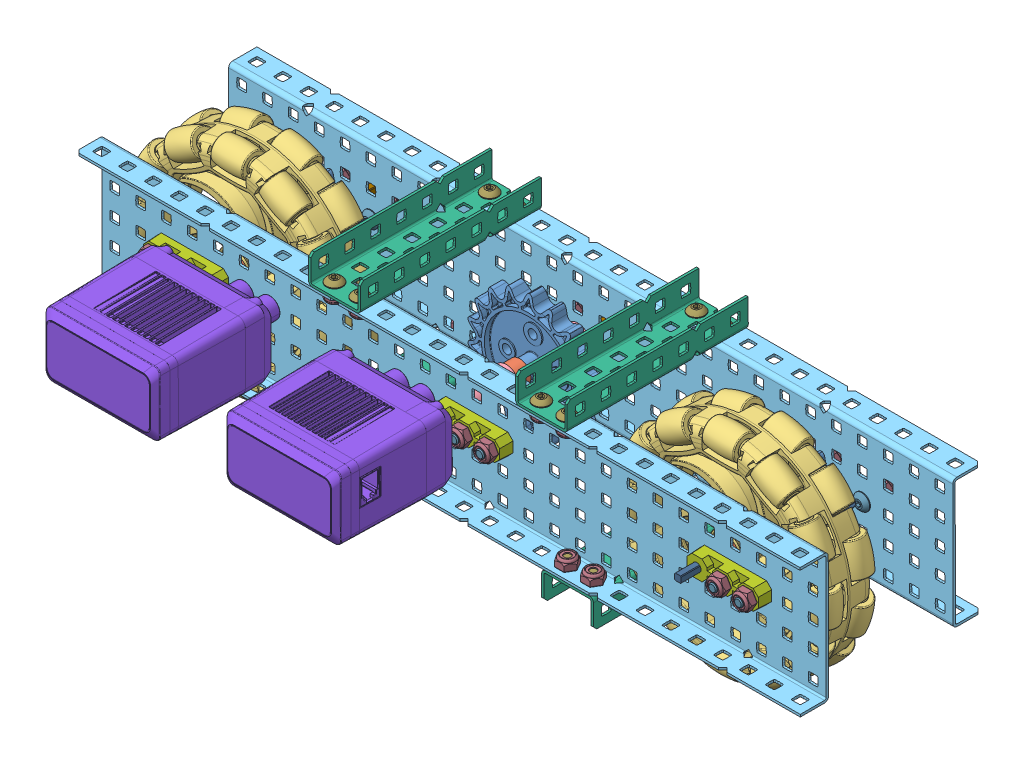
SolidWorks assembly tank_drive_left, configuration Default. Lengths in mm.
Overall size (355.74 109.64 150.55).
92 component instances, 14 part files, 192 mates.
Components (placement in the parent):
- Sprocket HS 18 Tooth-16: Sprocket HS 18 Tooth [Default] at (197.3923 25.5818 -147.38) size (60.62 61.51 15.88)
- Shaft Collar-3: Shaft Collar [Default] at (197.3923 25.5818 -136.1405) size (11 11.03 6.6)
- 4in Omni Directional Wheel-7: 4in Omni Directional Wheel [Default] at (197.3923 25.5818 -123.6356) x (1 0 0) z (0 -1 0) size (111.98 41.89 109.1)
- Sprocket HS 18 Tooth-18: Sprocket HS 18 Tooth [Default] at (311.692 25.8354 -147.38) size (60.62 61.51 15.88)
- Shaft Collar-6: Shaft Collar [Default] at (311.692 25.8354 -136.1405) size (11 11.03 6.6)
- Nylon Spacer .5 .5in-8: Nylon Spacer .5 .5in [Default] at (311.692 25.8354 -126.4885) x (1 0 0) z (0 -1 0) size (12.7 12.7 12.7)
- Sprocket HS 18 Tooth-19: Sprocket HS 18 Tooth [Default] at (438.6917 26.1172 -147.38) size (60.62 61.51 15.88)
- Shaft Collar-7: Shaft Collar [Default] at (438.6917 26.1172 -111.1307) size (11 11.03 6.6)
- Shaft Collar-8: Shaft Collar [Default] at (438.6917 26.1172 -136.1405) size (11 11.03 6.6)
- 4in Omni Directional Wheel-8: 4in Omni Directional Wheel [Default] at (438.6917 26.1172 -123.6356) x (1 0 0) z (0 -1 0) size (111.98 41.89 109.1)
- Shaft Collar-10: Shaft Collar [Default] at (197.3923 25.5818 -111.1307) size (11 11.03 6.6)
- Nylon Spacer .5 .5in-9: Nylon Spacer .5 .5in [Default] at (311.692 25.8354 -113.7885) x (1 0 0) z (0 -1 0) size (12.7 12.7 12.7)
- Nylon Spacer .5 .5in-10: Nylon Spacer .5 .5in [Default] at (438.6917 26.1172 -161.6675) x (1 0 0) z (0 -1 0) size (12.7 12.7 12.7)
- Nylon Spacer .5 .5in-11: Nylon Spacer .5 .5in [Default] at (311.692 25.8354 -161.6675) x (1 0 0) z (0 -1 0) size (12.7 12.7 12.7)
- Nylon Spacer .5 .5in-12: Nylon Spacer .5 .5in [Default] at (197.3923 25.5818 -161.6675) x (1 0 0) z (0 -1 0) size (12.7 12.7 12.7)
- C-Channel 1x5x1x28-6: C-Channel 1x5x1x28 [Default] at (77.7725 41.2118 -169.1859) x (0.999998 0.002219 0) z (0.002219 -0.999998 0) size (355.6 13.87 63.5)
- C-Channel 1x2x1x7-3: C-Channel 1x2x1x7 [Default] at (384.516 -7.1755 -119.4512) x (0 0 -1) z (0.999998 0.002219 0) size (88.9 13.87 25.4)
- C-Channel 1x5x1x28-7: C-Channel 1x5x1x28 [Default] at (558.2409 42.278 -105.6859) x (-0.999998 -0.002219 0) z (0.002219 -0.999998 0) size (355.6 13.87 63.5)
- Bearing Flat-7: Bearing Flat [Default] at (211.0801 38.3122 -16.7097) x (0 0 -1) z (-0.002219 0.999998 0) size (7.04 35.56 10.16)
- Bearing Flat-8: Bearing Flat [Default] at (350.7797 38.6222 -16.7097) x (0 0 -1) z (-0.002219 0.999998 0) size (7.04 35.56 10.16)
- Bearing Flat-9: Bearing Flat [Default] at (425.0039 13.3868 -16.7097) x (0 0 -1) z (0.002219 -0.999998 0) size (7.04 35.56 10.16)
- Bearing Flat-10: Bearing Flat [Default] at (465.1358 13.4759 -258.1621) x (0 0 1) z (0.00222 -0.999998 0) size (7.04 35.56 10.16)
- Bearing Flat-11: Bearing Flat [Default] at (338.1361 13.1941 -258.1621) x (0 0 1) z (0.002219 -0.999998 0) size (7.04 35.56 10.16)
- Bearing Flat-12: Bearing Flat [Default] at (223.8364 12.9404 -258.1621) x (0 0 1) z (0.00222 -0.999998 0) size (7.04 35.56 10.16)
- V5 Smart Motor-1: V5 Smart Motor [Default] at (210.0922 25.6099 -61.4859) x (-0.999998 -0.002219 0) z (0 0 -1) size (57.3 33 72.31)
- V5 Smart Motor-2: V5 Smart Motor [Default] at (298.992 25.8072 -61.4859) x (0.999998 0.002219 0) z (0 0 -1) size (57.3 33 72.31)
- Drive Shaft 4-inches long-1: Drive Shaft 4-inches long [Default] at (197.3923 25.5818 120.1773) x (-1 0 0) z (0 0 -1) size (3.17 3.17 101.34)
- Drive Shaft 4-inches long-2: Drive Shaft 4-inches long [Default] at (311.692 25.8354 120.1773) x (-1 0 0) z (0 0 -1) size (3.17 3.17 101.34)
- Drive Shaft 3.5-inches long-1: Drive Shaft 3.5-inches long [Default] at (438.6917 26.1172 126.0171) x (-1 0 0) z (0 0 -1) size (3.17 3.17 88.64)
- C-Channel 1x2x1x7-4: C-Channel 1x2x1x7 [Default] at (257.5163 -7.4573 -119.4512) x (0 0 -1) z (0.999998 0.002219 0) size (88.9 13.87 25.4)
- C-Channel 1x2x1x7-5: C-Channel 1x2x1x7 [Default] at (264.2691 58.3946 -119.4512) x (0 0 -1) z (-0.999998 -0.002219 0) size (88.9 13.87 25.4)
- C-Channel 1x2x1x7-6: C-Channel 1x2x1x7 [Default] at (365.8688 58.6201 -119.4512) x (0 0 -1) z (-0.999998 -0.002219 0) size (88.9 13.87 25.4)
- Screw 632 .25in-1: Screw 632 .25in [Default] at (222.7922 25.6381 -108.7085) x (0 0 1) z (-1 0 0) size (8.57 6.68 6.65)
- Screw 632 .25in-2: Screw 632 .25in [Default] at (210.0922 25.6099 -108.7085) x (0 0 1) z (-1 0 0) size (8.57 6.68 6.65)
- Screw 632 .25in-3: Screw 632 .25in [Default] at (286.2921 25.779 -108.7085) x (0 0 1) z (-1 0 0) size (8.57 6.68 6.65)
- Screw 632 .25in-4: Screw 632 .25in [Default] at (298.992 25.8072 -108.7085) x (0 0 1) z (-1 0 0) size (8.57 6.68 6.65)
- Screw 832 .25in-1: Screw 832 .25in [Default] at (362.4145 60.8223 -175.5359) x (0.002219 -0.999998 0) z (0 0 1) size (9.01 8.02 7.99)
- Screw 832 .25in-2: Screw 832 .25in [Default] at (387.9703 -9.3776 -175.5359) x (-0.002219 0.999998 0) z (-0.546742 -0.001213 0.8373) size (9.01 8.02 7.99)
- Screw 832 .25in-3: Screw 832 .25in [Default] at (248.2707 -9.6876 -175.5359) x (-0.002219 0.999998 0) z (0 0 1) size (9.01 8.02 7.99)
- Screw 832 .25in-4: Screw 832 .25in [Default] at (260.9706 -9.6594 -175.5359) x (-0.002219 0.999998 0) z (-0.546742 -0.001213 0.8373) size (9.01 8.02 7.99)
- Screw 832 .25in-5: Screw 832 .25in [Default] at (260.8147 60.5968 -175.5359) x (0.002219 -0.999998 0) z (0 0 1) size (9.01 8.02 7.99)
- Screw 832 .25in-6: Screw 832 .25in [Default] at (273.5147 60.625 -175.5359) x (0.002219 -0.999998 0) z (0 0 1) size (9.01 8.02 7.99)
- Screw 832 .25in-7: Screw 832 .25in [Default] at (375.2704 -9.4058 -175.5359) x (-0.002219 0.999998 0) z (-0.546742 -0.001213 0.8373) size (9.01 8.02 7.99)
- Screw 832 .25in-8: Screw 832 .25in [Default] at (375.1144 60.8504 -175.5359) x (0.002219 -0.999998 0) z (0 0 1) size (9.01 8.02 7.99)
- Screw 832 .25in-9: Screw 832 .25in [Default] at (248.2707 -9.6876 -99.3359) x (-0.002219 0.999998 0) z (-0.546742 -0.001213 0.8373) size (9.01 8.02 7.99)
- Screw 832 .25in-10: Screw 832 .25in [Default] at (273.5147 60.625 -99.3359) x (0.002219 -0.999998 0) z (0 0 1) size (9.01 8.02 7.99)
- Screw 832 .25in-11: Screw 832 .25in [Default] at (260.9706 -9.6594 -99.3359) x (-0.002219 0.999998 0) z (-0.546742 -0.001213 0.8373) size (9.01 8.02 7.99)
- Screw 832 .25in-12: Screw 832 .25in [Default] at (260.8147 60.5968 -99.3359) x (0.002219 -0.999998 0) z (0 0 1) size (9.01 8.02 7.99)
- Screw 832 .25in-13: Screw 832 .25in [Default] at (375.2704 -9.4058 -99.3359) x (-0.002219 0.999998 0) z (-0.546742 -0.001213 0.8373) size (9.01 8.02 7.99)
- Screw 832 .25in-14: Screw 832 .25in [Default] at (362.4145 60.8223 -99.3359) x (0.002219 -0.999998 0) z (0 0 1) size (9.01 8.02 7.99)
- Screw 832 .25in-15: Screw 832 .25in [Default] at (387.9703 -9.3776 -99.3359) x (-0.002219 0.999998 0) z (-0.546742 -0.001213 0.8373) size (9.01 8.02 7.99)
- Screw 832 .25in-16: Screw 832 .25in [Default] at (375.1144 60.8504 -99.3359) x (0.002219 -0.999998 0) z (0 0 1) size (9.01 8.02 7.99)
- Nut 832 Nylock-1: Nut 832 Nylock [Default] at (387.9602 -4.831 -175.5359) x (0.999998 0.002219 0) z (0 0 1) size (10.2 4.9 8.12)
- Nut 832 Nylock-2: Nut 832 Nylock [Default] at (375.2603 -4.8592 -175.5359) x (0.999998 0.002219 0) z (0 0 1) size (10.2 4.9 8.12)
- Nut 832 Nylock-3: Nut 832 Nylock [Default] at (260.9605 -5.1129 -175.5359) x (0.999998 0.002219 0) z (0 0 1) size (10.2 4.9 8.12)
- Nut 832 Nylock-4: Nut 832 Nylock [Default] at (248.2606 -5.141 -175.5359) x (0.999998 0.002219 0) z (0 0 1) size (10.2 4.9 8.12)
- Nut 832 Nylock-5: Nut 832 Nylock [Default] at (260.8248 56.0502 -175.5359) x (-0.837298 -0.001858 -0.546743) z (-0.546742 -0.001213 0.8373) size (10.2 4.9 8.12)
- Nut 832 Nylock-6: Nut 832 Nylock [Default] at (273.5248 56.0784 -175.5359) x (-0.837298 -0.001858 -0.546743) z (-0.546742 -0.001213 0.8373) size (10.2 4.9 8.12)
- Nut 832 Nylock-7: Nut 832 Nylock [Default] at (362.4246 56.2757 -175.5359) x (-0.837298 -0.001858 -0.546743) z (-0.546742 -0.001213 0.8373) size (10.2 4.9 8.12)
- Nut 832 Nylock-8: Nut 832 Nylock [Default] at (375.1245 56.3038 -175.5359) x (-0.837298 -0.001858 -0.546743) z (-0.546742 -0.001213 0.8373) size (10.2 4.9 8.12)
- Nut 832 Nylock-9: Nut 832 Nylock [Default] at (387.9602 -4.831 -99.3359) x (0.999998 0.002219 0) z (0 0 1) size (10.2 4.9 8.12)
- Nut 832 Nylock-10: Nut 832 Nylock [Default] at (375.2603 -4.8592 -99.3359) x (0.999998 0.002219 0) z (0 0 1) size (10.2 4.9 8.12)
- Nut 832 Nylock-11: Nut 832 Nylock [Default] at (260.9605 -5.1129 -99.3359) x (0.999998 0.002219 0) z (0 0 1) size (10.2 4.9 8.12)
- Nut 832 Nylock-12: Nut 832 Nylock [Default] at (248.2606 -5.141 -99.3359) x (0.999998 0.002219 0) z (0 0 1) size (10.2 4.9 8.12)
- Nut 832 Nylock-13: Nut 832 Nylock [Default] at (260.8248 56.0502 -99.3359) x (-0.837298 -0.001858 -0.546743) z (-0.546742 -0.001213 0.8373) size (10.2 4.9 8.12)
- Nut 832 Nylock-14: Nut 832 Nylock [Default] at (273.5248 56.0784 -99.3359) x (-0.837298 -0.001858 -0.546743) z (-0.546742 -0.001213 0.8373) size (10.2 4.9 8.12)
- Nut 832 Nylock-15: Nut 832 Nylock [Default] at (362.4246 56.2757 -99.3359) x (-0.837298 -0.001858 -0.546743) z (-0.546742 -0.001213 0.8373) size (10.2 4.9 8.12)
- Nut 832 Nylock-16: Nut 832 Nylock [Default] at (375.1245 56.3038 -99.3359) x (-0.837298 -0.001858 -0.546743) z (-0.546742 -0.001213 0.8373) size (10.2 4.9 8.12)
- Screw 832 .5in-1: Screw 832 .5in [Default] at (171.9923 25.5254 -109.0641) x (0 0 1) z (-1 0 0) size (15.36 8.02 7.99)
- Screw 832 .5in-2: Screw 832 .5in [Default] at (184.6923 25.5536 -109.0641) x (0 0 1) z (-1 0 0) size (15.36 8.02 7.99)
- Screw 832 .5in-3: Screw 832 .5in [Default] at (324.392 25.8636 -109.0641) x (0 0 1) z (-1 0 0) size (15.36 8.02 7.99)
- Screw 832 .5in-4: Screw 832 .5in [Default] at (337.0919 25.8918 -109.0641) x (0 0 1) z (-1 0 0) size (15.36 8.02 7.99)
- Screw 832 .5in-5: Screw 832 .5in [Default] at (451.3916 26.1454 -109.0641) x (0 0 1) z (-1 0 0) size (15.36 8.02 7.99)
- Screw 832 .5in-6: Screw 832 .5in [Default] at (464.0916 26.1736 -109.0641) x (0 0 1) z (-1 0 0) size (15.36 8.02 7.99)
- Screw 832 .5in-7: Screw 832 .5in [Default] at (451.3916 26.1454 -165.8077) x (0 0 -1) z (1 0 0) size (15.36 8.02 7.99)
- Screw 832 .5in-8: Screw 832 .5in [Default] at (425.9917 26.0891 -165.8077) x (0 0 -1) z (1 0 0) size (15.36 8.02 7.99)
- Screw 832 .5in-9: Screw 832 .5in [Default] at (324.392 25.8636 -165.8077) x (0 0 -1) z (1 0 0) size (15.36 8.02 7.99)
- Screw 832 .5in-10: Screw 832 .5in [Default] at (298.992 25.8072 -165.8077) x (0 0 -1) z (1 0 0) size (15.36 8.02 7.99)
- Screw 832 .5in-11: Screw 832 .5in [Default] at (210.0922 25.61 -165.8077) x (0 0 -1) z (1 0 0) size (15.36 8.02 7.99)
- Screw 832 .5in-12: Screw 832 .5in [Default] at (184.6923 25.5536 -165.8077) x (0 0 -1) z (1 0 0) size (15.36 8.02 7.99)
- Nut 832 Nylock-17: Nut 832 Nylock [Default] at (184.6923 25.5536 -99.3359) x (1 0 0) z (0 -1 0) size (10.2 4.9 8.12)
- Nut 832 Nylock-18: Nut 832 Nylock [Default] at (171.9923 25.5254 -99.3359) x (1 0 0) z (0 -1 0) size (10.2 4.9 8.12)
- Nut 832 Nylock-19: Nut 832 Nylock [Default] at (324.392 25.8636 -99.3359) x (1 0 0) z (0 -1 0) size (10.2 4.9 8.12)
- Nut 832 Nylock-20: Nut 832 Nylock [Default] at (337.0919 25.8918 -99.3359) x (1 0 0) z (0 -1 0) size (10.2 4.9 8.12)
- Nut 832 Nylock-21: Nut 832 Nylock [Default] at (451.3916 26.1454 -99.3359) x (1 0 0) z (0 -1 0) size (10.2 4.9 8.12)
- Nut 832 Nylock-22: Nut 832 Nylock [Default] at (464.0916 26.1736 -99.3359) x (1 0 0) z (0 -1 0) size (10.2 4.9 8.12)
- Nut 832 Nylock-23: Nut 832 Nylock [Default] at (451.3916 26.1454 -175.5359) x (1 0 0) z (0 1 0) size (10.2 4.9 8.12)
- Nut 832 Nylock-24: Nut 832 Nylock [Default] at (425.9917 26.0891 -175.5359) x (1 0 0) z (0 1 0) size (10.2 4.9 8.12)
- Nut 832 Nylock-25: Nut 832 Nylock [Default] at (324.392 25.8636 -175.5359) x (1 0 0) z (0 1 0) size (10.2 4.9 8.12)
- Nut 832 Nylock-26: Nut 832 Nylock [Default] at (298.992 25.8072 -175.5359) x (1 0 0) z (0 1 0) size (10.2 4.9 8.12)
- Nut 832 Nylock-27: Nut 832 Nylock [Default] at (210.0922 25.61 -175.5359) x (1 0 0) z (0 1 0) size (10.2 4.9 8.12)
- Nut 832 Nylock-28: Nut 832 Nylock [Default] at (184.6923 25.5536 -175.5359) x (1 0 0) z (0 1 0) size (10.2 4.9 8.12)
Mates (geometry in assembly coordinates):
- Concentric110: concentric: cylinder of Sprocket HS 18 Tooth-16 through (197.3923 25.5818 -132.4575) axis (0 0 -1) radius 1.651; cylinder of Shaft Collar-3 through (197.3923 25.5818 -139.4425) axis (0 0 1) radius 2.0955
- Coincident75: coincident: plane of Sprocket HS 18 Tooth-16 through (197.3923 25.5818 -139.4425) normal (0 0 1); circle of Shaft Collar-3
- Concentric111: concentric: cylinder of Shaft Collar-3 through (197.3923 25.5818 -139.4425) axis (0 0 1) radius 2.0955; cylinder of 4in Omni Directional Wheel-7 through (197.3923 25.5818 -155.0046) axis (0 0 1) radius 1.651
- Tangent19: tangent: plane of Shaft Collar-3 through (197.3923 25.5818 -132.8385) normal (0 0 1); sphere of 4in Omni Directional Wheel-7
- Concentric115: concentric: cylinder of Sprocket HS 18 Tooth-18 through (311.692 25.8354 -132.4575) axis (0 0 -1) radius 1.651; cylinder of Shaft Collar-6 through (311.692 25.8354 -139.4425) axis (0 0 1) radius 2.0955
- Coincident78: coincident: plane of Sprocket HS 18 Tooth-18 through (311.692 25.8354 -139.4425) normal (0 0 1); plane of Shaft Collar-6 through (311.692 25.8354 -139.4425) normal (0 0 -1)
- Concentric116: concentric: cylinder of Shaft Collar-6 through (311.692 25.8354 -139.4425) axis (0 0 1) radius 2.0955; cylinder of Nylon Spacer .5 .5in-8 through (311.692 25.8354 -120.1385) axis (0 0 -1) radius 2.4638
- Coincident79: coincident: plane of Shaft Collar-6 through (311.692 25.8354 -132.8385) normal (0 0 1); circle of Nylon Spacer .5 .5in-8
- Concentric141: concentric: cylinder of Sprocket HS 18 Tooth-19 through (438.6917 26.1172 -132.4575) axis (0 0 -1) radius 1.651; cylinder of Shaft Collar-8 through (438.6917 26.1172 -139.4425) axis (0 0 1) radius 2.0955
- Coincident91: coincident: plane of Sprocket HS 18 Tooth-19 through (438.6917 26.1172 -139.4425) normal (0 0 1); plane of Shaft Collar-8 through (438.6917 26.1172 -139.4425) normal (0 0 -1)
- Concentric142: concentric: cylinder of Shaft Collar-8 through (438.6917 26.1172 -139.4425) axis (0 0 1) radius 2.0955; cylinder of 4in Omni Directional Wheel-8 through (438.6917 26.1172 -155.0046) axis (0 0 1) radius 1.651
- Tangent20: tangent: plane of Shaft Collar-8 through (438.6917 26.1172 -132.8385) normal (0 0 1); sphere of 4in Omni Directional Wheel-8
- Concentric143: concentric: cylinder of Shaft Collar-7 through (438.6917 26.1172 -114.4327) axis (0 0 1) radius 2.0955; cylinder of 4in Omni Directional Wheel-8 through (438.6917 26.1172 -155.0046) axis (0 0 1) radius 1.651
- Tangent21: tangent: plane of Shaft Collar-7 through (438.6917 26.1172 -114.4327) normal (0 0 -1); sphere of 4in Omni Directional Wheel-8
- Concentric146: concentric: cylinder of 4in Omni Directional Wheel-7 through (197.3923 25.5818 -155.0046) axis (0 0 1) radius 1.651; cylinder of Shaft Collar-10 through (197.3923 25.5818 -114.4327) axis (0 0 1) radius 2.0955
- Tangent22: tangent: sphere of 4in Omni Directional Wheel-7; plane of Shaft Collar-10 through (197.3923 25.5818 -114.4327) normal (0 0 -1)
- Coincident96: coincident: circle of Nylon Spacer .5 .5in-8; cylinder of Nylon Spacer .5 .5in-9 through (311.692 25.8354 -107.4385) axis (0 0 -1) radius 2.4638
- Coincident97: coincident: circle of Nylon Spacer .5 .5in-8; circle of Nylon Spacer .5 .5in-9
- Concentric151: concentric: cylinder of Sprocket HS 18 Tooth-19 through (438.6917 26.1172 -132.4575) axis (0 0 -1) radius 1.651; circle of Nylon Spacer .5 .5in-10
- Coincident98: coincident: plane of Sprocket HS 18 Tooth-19 through (438.6917 26.1172 -155.3175) normal (0 0 -1); plane of Nylon Spacer .5 .5in-10 through (438.6917 26.1172 -155.3175) normal (0 0 1)
- Concentric152: concentric: cylinder of Sprocket HS 18 Tooth-18 through (311.692 25.8354 -132.4575) axis (0 0 -1) radius 1.651; cylinder of Nylon Spacer .5 .5in-11 through (311.692 25.8354 -155.3175) axis (0 0 -1) radius 2.4638
- Coincident99: coincident: plane of Sprocket HS 18 Tooth-18 through (311.692 25.8354 -155.3175) normal (0 0 -1); circle of Nylon Spacer .5 .5in-11
- Concentric153: concentric: cylinder of Sprocket HS 18 Tooth-16 through (197.3923 25.5818 -132.4575) axis (0 0 -1) radius 1.651; cylinder of Nylon Spacer .5 .5in-12 through (197.3923 25.5818 -155.3175) axis (0 0 -1) radius 2.4638
- Coincident100: coincident: plane of Sprocket HS 18 Tooth-16 through (197.3923 25.5818 -155.3175) normal (0 0 -1); circle of Nylon Spacer .5 .5in-12
- Concentric154: concentric: cylinder of Nylon Spacer .5 .5in-10 through (438.6917 26.1172 -155.3175) axis (0 0 -1) radius 2.4638; cylinder of C-Channel 1x5x1x28-6 through (438.6917 26.1172 -170.5575) axis (0 0 1) radius 2.413
- Concentric155: concentric: cylinder of Nylon Spacer .5 .5in-12 through (197.3923 25.5818 -155.3175) axis (0 0 -1) radius 2.4638; cylinder of C-Channel 1x5x1x28-6 through (197.3923 25.5818 -170.5575) axis (0 0 1) radius 2.413
- Coincident101: coincident: plane of Nylon Spacer .5 .5in-12 through (197.3923 25.5818 -168.0175) normal (0 0 -1); plane of C-Channel 1x5x1x28-6 through (51.4137 -6.7463 -168.0175) normal (0 0 1)
- Concentric156: concentric: cylinder of Nylon Spacer .5 .5in-11 through (311.692 25.8354 -155.3175) axis (0 0 -1) radius 2.4638; cylinder of C-Channel 1x5x1x28-6 through (311.692 25.8354 -170.5575) axis (0 0 1) radius 2.413
- Concentric157: concentric: cylinder of C-Channel 1x5x1x28-6 through (387.8219 57.5004 -175.5359) axis (0.002219 -0.999998 0) radius 2.413; cylinder of C-Channel 1x2x1x7-3 through (387.9685 -8.5394 -175.5359) axis (-0.002219 0.999998 0) radius 2.413
- Concentric158: concentric: cylinder of C-Channel 1x5x1x28-6 through (375.1219 57.4722 -175.5359) axis (0.002219 -0.999998 0) radius 2.413; cylinder of C-Channel 1x2x1x7-3 through (375.2685 -8.5676 -175.5359) axis (-0.002219 0.999998 0) radius 2.413
- Coincident102: coincident: plane of C-Channel 1x5x1x28-6 through (51.4137 -6.7463 -181.8859) normal (0.002219 -0.999998 0); plane of C-Channel 1x2x1x7-3 through (394.3128 -5.9853 -92.9859) normal (-0.002219 0.999998 0)
- Concentric159: concentric: cylinder of C-Channel 1x2x1x7-3 through (387.9685 -8.5394 -99.3359) axis (-0.002219 0.999998 0) radius 2.413; cylinder of C-Channel 1x5x1x28-7 through (387.8219 57.5004 -99.3359) axis (0.002219 -0.999998 0) radius 2.413
- Concentric160: concentric: cylinder of C-Channel 1x2x1x7-3 through (375.2685 -8.5676 -99.3359) axis (-0.002219 0.999998 0) radius 2.413; cylinder of C-Channel 1x5x1x28-7 through (375.1219 57.4722 -99.3359) axis (0.002219 -0.999998 0) radius 2.413
- Coincident103: coincident: plane of C-Channel 1x2x1x7-3 through (394.3128 -5.9853 -92.9859) normal (-0.002219 0.999998 0); plane of C-Channel 1x5x1x28-7 through (584.8123 -5.5626 -92.9859) normal (0.002219 -0.999998 0)
- Concentric161: concentric: cylinder of C-Channel 1x5x1x28-7 through (197.3923 25.5818 -104.3143) axis (0 0 -1) radius 2.413; cylinder of Bearing Flat-7 through (197.3923 25.5818 -99.3359) axis (0 0 -1) radius 2.1209
- Concentric162: concentric: cylinder of C-Channel 1x5x1x28-7 through (171.9923 25.5254 -104.3143) axis (0 0 -1) radius 2.413; cylinder of Bearing Flat-7 through (171.9923 25.5254 -99.3359) axis (0 0 -1) radius 2.1209
- Coincident104: coincident: plane of C-Channel 1x5x1x28-7 through (584.8123 -5.5626 -105.6859) normal (0 0 1); plane of Bearing Flat-7 through (166.9199 20.4304 -105.6859) normal (0 0 -1)
- Concentric163: concentric: cylinder of C-Channel 1x5x1x28-7 through (337.0919 25.8918 -104.3143) axis (0 0 -1) radius 2.413; cylinder of Bearing Flat-8 through (337.0919 25.8918 -99.3359) axis (0 0 -1) radius 2.1209
- Concentric164: concentric: cylinder of C-Channel 1x5x1x28-7 through (311.692 25.8354 -104.3143) axis (0 0 -1) radius 2.413; cylinder of Bearing Flat-8 through (311.692 25.8354 -99.3359) axis (0 0 -1) radius 2.1209
- Coincident105: coincident: plane of C-Channel 1x5x1x28-7 through (584.8123 -5.5626 -105.6859) normal (0 0 1); plane of Bearing Flat-8 through (306.6196 20.7405 -105.6859) normal (0 0 -1)
- Concentric165: concentric: cylinder of C-Channel 1x5x1x28-7 through (438.6917 26.1172 -104.3143) axis (0 0 -1) radius 2.413; cylinder of Bearing Flat-9 through (438.6917 26.1172 -99.3359) axis (0 0 -1) radius 2.1209
- Concentric166: concentric: cylinder of C-Channel 1x5x1x28-7 through (464.0916 26.1736 -104.3143) axis (0 0 -1) radius 2.413; cylinder of Bearing Flat-9 through (464.0916 26.1736 -99.3359) axis (0 0 -1) radius 2.1209
- Coincident106: coincident: plane of C-Channel 1x5x1x28-7 through (584.8123 -5.5626 -105.6859) normal (0 0 1); plane of Bearing Flat-9 through (469.164 31.2686 -105.6859) normal (0 0 -1)
- Concentric167: concentric: cylinder of C-Channel 1x5x1x28-6 through (438.6917 26.1172 -170.5575) axis (0 0 1) radius 2.413; cylinder of Bearing Flat-10 through (438.6917 26.1172 -169.1859) axis (0 0 -1) radius 2.1209
- Concentric168: concentric: cylinder of C-Channel 1x5x1x28-6 through (425.9917 26.0891 -170.5575) axis (0 0 1) radius 2.413; cylinder of Bearing Flat-10 through (425.9917 26.0891 -175.5359) axis (0 0 1) radius 2.1209
- Coincident107: coincident: plane of C-Channel 1x5x1x28-6 through (51.4137 -6.7463 -169.1859) normal (0 0 -1); plane of Bearing Flat-10 through (420.8968 31.1614 -169.1859) normal (0 0 1)
- Concentric169: concentric: cylinder of C-Channel 1x5x1x28-6 through (311.692 25.8354 -170.5575) axis (0 0 1) radius 2.413; cylinder of Bearing Flat-11 through (311.692 25.8354 -169.1859) axis (0 0 -1) radius 2.1209
- Concentric170: concentric: cylinder of C-Channel 1x5x1x28-6 through (324.392 25.8636 -170.5575) axis (0 0 1) radius 2.413; cylinder of Bearing Flat-11 through (324.392 25.8636 -175.5359) axis (0 0 1) radius 2.1209
- Coincident108: coincident: plane of C-Channel 1x5x1x28-6 through (51.4137 -6.7463 -169.1859) normal (0 0 -1); plane of Bearing Flat-11 through (293.8971 30.8796 -169.1859) normal (0 0 1)
- Concentric171: concentric: cylinder of C-Channel 1x5x1x28-6 through (197.3923 25.5818 -170.5575) axis (0 0 1) radius 2.413; cylinder of Bearing Flat-12 through (197.3923 25.5818 -169.1859) axis (0 0 -1) radius 2.1209
- Concentric172: concentric: cylinder of C-Channel 1x5x1x28-6 through (184.6923 25.5536 -170.5575) axis (0 0 1) radius 2.413; cylinder of Bearing Flat-12 through (184.6923 25.5536 -175.5359) axis (0 0 1) radius 2.1209
- Coincident109: coincident: plane of C-Channel 1x5x1x28-6 through (51.4137 -6.7463 -169.1859) normal (0 0 -1); plane of Bearing Flat-12 through (179.5974 30.626 -169.1859) normal (0 0 1)
- Concentric173: concentric: cylinder of C-Channel 1x5x1x28-7 through (222.7922 25.6381 -104.3143) axis (0 0 -1) radius 2.413; cylinder of V5 Smart Motor-1 through (222.7922 25.6381 -106.3859) axis (0 0 -1) radius 1.7272
- Concentric174: concentric: cylinder of C-Channel 1x5x1x28-7 through (210.0922 25.6099 -104.3143) axis (0 0 -1) radius 2.413; cylinder of V5 Smart Motor-1 through (210.0922 25.6099 -106.3859) axis (0 0 -1) radius 1.7272
- Coincident110: coincident: plane of C-Channel 1x5x1x28-7 through (584.8123 -5.5626 -105.6859) normal (0 0 1); plane of V5 Smart Motor-1 through (210.0922 25.6099 -105.6859) normal (0 0 -1)
- Concentric175: concentric: cylinder of C-Channel 1x5x1x28-7 through (286.2921 25.779 -104.3143) axis (0 0 -1) radius 2.413; cylinder of V5 Smart Motor-2 through (286.2921 25.779 -106.3859) axis (0 0 -1) radius 1.7272
- Concentric176: concentric: cylinder of C-Channel 1x5x1x28-7 through (298.992 25.8072 -104.3143) axis (0 0 -1) radius 2.413; cylinder of V5 Smart Motor-2 through (298.992 25.8072 -106.3859) axis (0 0 -1) radius 1.7272
- Coincident111: coincident: plane of C-Channel 1x5x1x28-7 through (584.8123 -5.5626 -105.6859) normal (0 0 1); plane of V5 Smart Motor-2 through (298.992 25.8072 -105.6859) normal (0 0 -1)
- Concentric177: concentric: cylinder of Bearing Flat-12 through (197.3923 25.5818 -169.1859) axis (0 0 -1) radius 2.1209; sphere of Drive Shaft 4-inches long-1
- Coincident112: coincident: plane of V5 Smart Motor-1 through (197.3923 25.5818 -83.2859) normal (0 0 -1); plane of Drive Shaft 4-inches long-1 through (198.9798 23.9943 -83.2859) normal (0 0 1)
- Concentric178: concentric: cylinder of Bearing Flat-11 through (311.692 25.8354 -169.1859) axis (0 0 -1) radius 2.1209; sphere of Drive Shaft 4-inches long-2
- Coincident113: coincident: plane of V5 Smart Motor-2 through (311.692 25.8354 -83.2859) normal (0 0 -1); plane of Drive Shaft 4-inches long-2 through (313.2795 24.2479 -83.2859) normal (0 0 1)
- Concentric179: concentric: cylinder of Bearing Flat-10 through (438.6917 26.1172 -169.1859) axis (0 0 -1) radius 2.1209; sphere of Drive Shaft 3.5-inches long-1
- Concentric180: concentric: cylinder of C-Channel 1x5x1x28-6 through (260.8222 57.2186 -175.5359) axis (0.002219 -0.999998 0) radius 2.413; cylinder of C-Channel 1x2x1x7-4 through (260.9688 -8.8212 -175.5359) axis (-0.002219 0.999998 0) radius 2.413
- Concentric181: concentric: cylinder of C-Channel 1x5x1x28-6 through (248.1223 57.1904 -175.5359) axis (0.002219 -0.999998 0) radius 2.413; cylinder of C-Channel 1x2x1x7-4 through (248.2688 -8.8494 -175.5359) axis (-0.002219 0.999998 0) radius 2.413
- Coincident114: coincident: line of C-Channel 1x5x1x28-6 through (243.9402 -6.319 -181.8859) axis (0.999998 0.002219 0); plane of C-Channel 1x2x1x7-4 through (267.3131 -6.2672 -92.9859) normal (-0.002219 0.999998 0)
- Concentric182: concentric: cylinder of C-Channel 1x5x1x28-7 through (248.1223 57.1904 -99.3359) axis (0.002219 -0.999998 0) radius 2.413; cylinder of C-Channel 1x2x1x7-4 through (248.2688 -8.8494 -99.3359) axis (-0.002219 0.999998 0) radius 2.413
- Concentric183: concentric: cylinder of C-Channel 1x5x1x28-6 through (362.422 57.4441 -175.5359) axis (0.002219 -0.999998 0) radius 2.413; cylinder of C-Channel 1x2x1x7-6 through (362.4163 59.9841 -175.5359) axis (0.002219 -0.999998 0) radius 2.413
- Concentric184: concentric: cylinder of C-Channel 1x5x1x28-7 through (375.1219 57.4722 -99.3359) axis (0.002219 -0.999998 0) radius 2.413; cylinder of C-Channel 1x2x1x7-6 through (375.1163 60.0122 -99.3359) axis (0.002219 -0.999998 0) radius 2.413
- Coincident115: coincident: plane of C-Channel 1x5x1x28-6 through (51.2727 56.7536 -169.1859) normal (-0.002219 0.999998 0); plane of C-Channel 1x2x1x7-6 through (356.072 57.43 -92.9859) normal (0.002219 -0.999998 0)
- Concentric185: concentric: cylinder of C-Channel 1x5x1x28-6 through (260.8222 57.2186 -175.5359) axis (0.002219 -0.999998 0) radius 2.413; cylinder of C-Channel 1x2x1x7-5 through (260.8166 59.7586 -175.5359) axis (0.002219 -0.999998 0) radius 2.413
- Concentric186: concentric: cylinder of C-Channel 1x5x1x28-7 through (273.5222 57.2468 -99.3359) axis (0.002219 -0.999998 0) radius 2.413; cylinder of C-Channel 1x2x1x7-5 through (273.5166 59.7868 -99.3359) axis (0.002219 -0.999998 0) radius 2.413
- Coincident116: coincident: plane of C-Channel 1x5x1x28-6 through (51.2727 56.7536 -169.1859) normal (-0.002219 0.999998 0); plane of C-Channel 1x2x1x7-5 through (254.4722 57.2045 -92.9859) normal (0.002219 -0.999998 0)
- Concentric187: concentric: cylinder of V5 Smart Motor-1 through (222.7922 25.6381 -106.3859) axis (0 0 -1) radius 1.7272; cylinder of Screw 632 .25in-1 through (222.7922 25.6381 -108.7085) axis (0 0 -1) radius 1.7082
- Concentric188: concentric: cylinder of V5 Smart Motor-1 through (210.0922 25.6099 -106.3859) axis (0 0 -1) radius 1.7272; cylinder of Screw 632 .25in-2 through (210.0922 25.6099 -108.7085) axis (0 0 -1) radius 1.7082
- Coincident117: coincident: plane of C-Channel 1x5x1x28-7 through (584.8123 -5.5626 -106.8543) normal (0 0 -1); plane of Screw 632 .25in-2 through (210.0922 27.3181 -106.8543) normal (0 0 1)
- Coincident118: coincident: plane of C-Channel 1x5x1x28-7 through (584.8123 -5.5626 -106.8543) normal (0 0 -1); plane of Screw 632 .25in-1 through (222.7922 27.3463 -106.8543) normal (0 0 1)
- Concentric189: concentric: cylinder of V5 Smart Motor-2 through (286.2921 25.779 -106.3859) axis (0 0 -1) radius 1.7272; cylinder of Screw 632 .25in-3 through (286.2921 25.779 -108.7085) axis (0 0 -1) radius 1.7082
- Concentric190: concentric: cylinder of V5 Smart Motor-2 through (298.992 25.8072 -106.3859) axis (0 0 -1) radius 1.7272; cylinder of Screw 632 .25in-4 through (298.992 25.8072 -108.7085) axis (0 0 -1) radius 1.7082
- Coincident119: coincident: plane of C-Channel 1x5x1x28-7 through (584.8123 -5.5626 -106.8543) normal (0 0 -1); plane of Screw 632 .25in-3 through (286.2921 27.4872 -106.8543) normal (0 0 1)
- Coincident120: coincident: plane of C-Channel 1x5x1x28-7 through (584.8123 -5.5626 -106.8543) normal (0 0 -1); plane of Screw 632 .25in-4 through (298.992 27.5154 -106.8543) normal (0 0 1)
- Concentric191: concentric: cylinder of C-Channel 1x5x1x28-6 through (260.8222 57.2186 -175.5359) axis (0.002219 -0.999998 0) radius 2.413; cylinder of Screw 832 .25in-4 through (260.9706 -9.6594 -175.5359) axis (0.002219 -0.999998 0) radius 2.0828
- Coincident121: coincident: plane of C-Channel 1x2x1x7-4 through (267.3157 -7.4356 -92.9859) normal (0.002219 -0.999998 0); plane of Screw 832 .25in-4 through (259.2218 -7.4535 -176.6747) normal (-0.002219 0.999998 0)
- Concentric193: concentric: cylinder of C-Channel 1x5x1x28-6 through (248.1223 57.1904 -175.5359) axis (0.002219 -0.999998 0) radius 2.413; cylinder of Screw 832 .25in-3 through (248.2707 -9.6876 -175.5359) axis (0.002219 -0.999998 0) radius 2.0828
- Coincident122: coincident: plane of C-Channel 1x2x1x7-4 through (267.3157 -7.4356 -92.9859) normal (0.002219 -0.999998 0); plane of Screw 832 .25in-3 through (246.183 -7.4825 -175.5359) normal (-0.002219 0.999998 0)
- Concentric194: concentric: cylinder of C-Channel 1x5x1x28-6 through (375.1219 57.4722 -175.5359) axis (0.002219 -0.999998 0) radius 2.413; cylinder of Screw 832 .25in-7 through (375.2704 -9.4058 -175.5359) axis (0.002219 -0.999998 0) radius 2.0828
- Coincident123: coincident: plane of C-Channel 1x2x1x7-3 through (394.3154 -7.1537 -92.9859) normal (0.002219 -0.999998 0); plane of Screw 832 .25in-7 through (373.5215 -7.1999 -176.6747) normal (-0.002219 0.999998 0)
- Concentric195: concentric: cylinder of C-Channel 1x2x1x7-3 through (387.9685 -8.5394 -175.5359) axis (-0.002219 0.999998 0) radius 2.413; cylinder of Screw 832 .25in-2 through (387.9703 -9.3776 -175.5359) axis (0.002219 -0.999998 0) radius 2.0828
- Coincident124: coincident: plane of C-Channel 1x2x1x7-3 through (394.3154 -7.1537 -92.9859) normal (0.002219 -0.999998 0); circle of Screw 832 .25in-2
- Concentric196: concentric: cylinder of C-Channel 1x2x1x7-6 through (375.1163 60.0122 -175.5359) axis (0.002219 -0.999998 0) radius 2.413; cylinder of Screw 832 .25in-8 through (375.1144 60.8504 -175.5359) axis (-0.002219 0.999998 0) radius 2.0828
- Coincident125: coincident: plane of C-Channel 1x2x1x7-6 through (356.0694 58.5984 -92.9859) normal (-0.002219 0.999998 0); plane of Screw 832 .25in-8 through (377.2021 58.6453 -175.5359) normal (0.002219 -0.999998 0)
- Concentric197: concentric: cylinder of C-Channel 1x2x1x7-6 through (362.4163 59.9841 -175.5359) axis (0.002219 -0.999998 0) radius 2.413; cylinder of Screw 832 .25in-1 through (362.4145 60.8223 -175.5359) axis (-0.002219 0.999998 0) radius 2.0828
- Concentric198: concentric: cylinder of C-Channel 1x2x1x7-5 through (273.5166 59.7868 -175.5359) axis (0.002219 -0.999998 0) radius 2.413; cylinder of Screw 832 .25in-6 through (273.5147 60.625 -175.5359) axis (-0.002219 0.999998 0) radius 2.0828
- Coincident129: coincident: line of C-Channel 1x2x1x7-5 through (277.8884 58.4249 -181.8859) axis (-0.999998 -0.002219 0); plane of Screw 832 .25in-6 through (275.6024 58.4198 -175.5359) normal (0.002219 -0.999998 0)
- Concentric199: concentric: cylinder of C-Channel 1x2x1x7-5 through (260.8166 59.7586 -175.5359) axis (0.002219 -0.999998 0) radius 2.413; cylinder of Screw 832 .25in-5 through (260.8147 60.5968 -175.5359) axis (-0.002219 0.999998 0) radius 2.0828
- Coincident130: coincident: plane of C-Channel 1x2x1x7-5 through (254.4696 58.3729 -92.9859) normal (-0.002219 0.999998 0); circle of Screw 832 .25in-5
- Concentric200: concentric: cylinder of C-Channel 1x5x1x28-7 through (248.1223 57.1904 -99.3359) axis (0.002219 -0.999998 0) radius 2.413; cylinder of Screw 832 .25in-9 through (248.2707 -9.6876 -99.3359) axis (0.002219 -0.999998 0) radius 2.0828
- Coincident131: coincident: line of C-Channel 1x2x1x7-4 through (243.897 -7.4875 -92.9859) axis (0.999998 0.002219 0); plane of Screw 832 .25in-9 through (246.5218 -7.4817 -100.4747) normal (-0.002219 0.999998 0)
- Concentric201: concentric: cylinder of C-Channel 1x5x1x28-7 through (260.8222 57.2186 -99.3359) axis (0.002219 -0.999998 0) radius 2.413; cylinder of Screw 832 .25in-11 through (260.9706 -9.6594 -99.3359) axis (0.002219 -0.999998 0) radius 2.0828
- Coincident133: coincident: line of C-Channel 1x2x1x7-4 through (243.897 -7.4875 -92.9859) axis (0.999998 0.002219 0); plane of Screw 832 .25in-11 through (259.2218 -7.4535 -100.4747) normal (-0.002219 0.999998 0)
- Concentric202: concentric: cylinder of C-Channel 1x2x1x7-5 through (260.8166 59.7586 -99.3359) axis (0.002219 -0.999998 0) radius 2.413; cylinder of Screw 832 .25in-12 through (260.8147 60.5968 -99.3359) axis (-0.002219 0.999998 0) radius 2.0828
- Coincident134: coincident: plane of C-Channel 1x2x1x7-5 through (254.4696 58.3729 -92.9859) normal (-0.002219 0.999998 0); circle of Screw 832 .25in-12
- Concentric203: concentric: cylinder of C-Channel 1x2x1x7-5 through (273.5166 59.7868 -99.3359) axis (0.002219 -0.999998 0) radius 2.413; cylinder of Screw 832 .25in-10 through (273.5147 60.625 -99.3359) axis (-0.002219 0.999998 0) radius 2.0828
- Coincident135: coincident: plane of C-Channel 1x2x1x7-5 through (254.4696 58.3729 -92.9859) normal (-0.002219 0.999998 0); circle of Screw 832 .25in-10
- Concentric204: concentric: cylinder of C-Channel 1x5x1x28-7 through (375.1219 57.4722 -99.3359) axis (0.002219 -0.999998 0) radius 2.413; cylinder of Screw 832 .25in-13 through (375.2704 -9.4058 -99.3359) axis (0.002219 -0.999998 0) radius 2.0828
- Coincident136: coincident: line of C-Channel 1x2x1x7-3 through (370.8967 -7.2057 -92.9859) axis (0.999998 0.002219 0); plane of Screw 832 .25in-13 through (373.5215 -7.1999 -100.4747) normal (-0.002219 0.999998 0)
- Concentric205: concentric: cylinder of C-Channel 1x5x1x28-7 through (387.8219 57.5004 -99.3359) axis (0.002219 -0.999998 0) radius 2.413; cylinder of Screw 832 .25in-15 through (387.9703 -9.3776 -99.3359) axis (0.002219 -0.999998 0) radius 2.0828
- Coincident137: coincident: line of C-Channel 1x2x1x7-3 through (370.8967 -7.2057 -92.9859) axis (0.999998 0.002219 0); plane of Screw 832 .25in-15 through (386.2215 -7.1717 -100.4747) normal (-0.002219 0.999998 0)
- Concentric206: concentric: cylinder of C-Channel 1x2x1x7-6 through (362.4163 59.9841 -99.3359) axis (0.002219 -0.999998 0) radius 2.413; cylinder of Screw 832 .25in-14 through (362.4145 60.8223 -99.3359) axis (-0.002219 0.999998 0) radius 2.0828
- Coincident138: coincident: plane of C-Channel 1x2x1x7-6 through (356.0694 58.5984 -92.9859) normal (-0.002219 0.999998 0); circle of Screw 832 .25in-14
- Concentric207: concentric: cylinder of C-Channel 1x2x1x7-6 through (375.1163 60.0122 -99.3359) axis (0.002219 -0.999998 0) radius 2.413; cylinder of Screw 832 .25in-16 through (375.1144 60.8504 -99.3359) axis (-0.002219 0.999998 0) radius 2.0828
- Coincident139: coincident: plane of C-Channel 1x2x1x7-6 through (356.0694 58.5984 -92.9859) normal (-0.002219 0.999998 0); circle of Screw 832 .25in-16
- Concentric208: concentric: cylinder of Screw 832 .25in-15 through (387.9703 -9.3776 -99.3359) axis (0.002219 -0.999998 0) radius 2.0828; cylinder of Nut 832 Nylock-9 through (387.9602 -4.831 -99.3359) axis (-0.002219 0.999998 0) radius 1.6955
- Coincident140: coincident: line of C-Channel 1x5x1x28-7 through (332.8374 -4.9533 -92.9859) axis (0.999998 0.002219 0); plane of Nut 832 Nylock-9 through (390.3034 -4.8258 -95.2775) normal (0.002219 -0.999998 0)
- Concentric209: concentric: cylinder of Screw 832 .25in-13 through (375.2704 -9.4058 -99.3359) axis (0.002219 -0.999998 0) radius 2.0828; cylinder of Nut 832 Nylock-10 through (375.2603 -4.8592 -99.3359) axis (-0.002219 0.999998 0) radius 1.6955
- Coincident141: coincident: plane of C-Channel 1x5x1x28-7 through (584.8097 -4.3942 -92.9859) normal (-0.002219 0.999998 0); plane of Nut 832 Nylock-10 through (377.6034 -4.854 -95.2775) normal (0.002219 -0.999998 0)
- Concentric210: concentric: cylinder of Screw 832 .25in-9 through (248.2707 -9.6876 -99.3359) axis (0.002219 -0.999998 0) radius 2.0828; cylinder of Nut 832 Nylock-12 through (248.2606 -5.141 -99.3359) axis (-0.002219 0.999998 0) radius 1.6955
- Concentric211: concentric: cylinder of Screw 832 .25in-11 through (260.9706 -9.6594 -99.3359) axis (0.002219 -0.999998 0) radius 2.0828; cylinder of Nut 832 Nylock-11 through (260.9605 -5.1129 -99.3359) axis (-0.002219 0.999998 0) radius 1.6955
- Coincident142: coincident: line of C-Channel 1x5x1x28-7 through (205.8377 -5.2352 -92.9859) axis (0.999998 0.002219 0); plane of Nut 832 Nylock-12 through (250.6037 -5.1358 -95.2775) normal (0.002219 -0.999998 0)
- Coincident143: coincident: line of C-Channel 1x5x1x28-7 through (205.8377 -5.2352 -92.9859) axis (0.999998 0.002219 0); plane of Nut 832 Nylock-11 through (263.3037 -5.1077 -95.2775) normal (0.002219 -0.999998 0)
- Concentric212: concentric: cylinder of Screw 832 .25in-12 through (260.8147 60.5968 -99.3359) axis (-0.002219 0.999998 0) radius 2.0828; cylinder of Nut 832 Nylock-13 through (260.8248 56.0502 -99.3359) axis (0.002219 -0.999998 0) radius 1.6955
- Concentric213: concentric: cylinder of Screw 832 .25in-10 through (273.5147 60.625 -99.3359) axis (-0.002219 0.999998 0) radius 2.0828; cylinder of Nut 832 Nylock-14 through (273.5248 56.0784 -99.3359) axis (0.002219 -0.999998 0) radius 1.6955
- Coincident144: coincident: line of C-Channel 1x5x1x28-7 through (265.1478 56.0598 -92.9859) axis (-0.999998 -0.002219 0); plane of Nut 832 Nylock-13 through (256.644 56.0409 -97.2189) normal (-0.002219 0.999998 0)
- Coincident145: coincident: line of C-Channel 1x5x1x28-7 through (328.6477 56.2007 -92.9859) axis (-0.999998 -0.002219 0); plane of Nut 832 Nylock-14 through (269.3439 56.0691 -97.2189) normal (-0.002219 0.999998 0)
- Concentric214: concentric: cylinder of Screw 832 .25in-14 through (362.4145 60.8223 -99.3359) axis (-0.002219 0.999998 0) radius 2.0828; cylinder of Nut 832 Nylock-15 through (362.4246 56.2757 -99.3359) axis (0.002219 -0.999998 0) radius 1.6955
- Concentric215: concentric: cylinder of Screw 832 .25in-16 through (375.1144 60.8504 -99.3359) axis (-0.002219 0.999998 0) radius 2.0828; cylinder of Nut 832 Nylock-16 through (375.1245 56.3038 -99.3359) axis (0.002219 -0.999998 0) radius 1.6955
- Coincident146: coincident: line of C-Channel 1x5x1x28-7 through (392.1475 56.3416 -92.9859) axis (-0.999998 -0.002219 0); plane of Nut 832 Nylock-16 through (370.9437 56.2946 -97.2189) normal (-0.002219 0.999998 0)
- Coincident147: coincident: line of C-Channel 1x5x1x28-7 through (392.1475 56.3416 -92.9859) axis (-0.999998 -0.002219 0); plane of Nut 832 Nylock-15 through (358.2437 56.2664 -97.2189) normal (-0.002219 0.999998 0)
- Concentric216: concentric: cylinder of Screw 832 .25in-7 through (375.2704 -9.4058 -175.5359) axis (0.002219 -0.999998 0) radius 2.0828; cylinder of Nut 832 Nylock-2 through (375.2603 -4.8592 -175.5359) axis (-0.002219 0.999998 0) radius 1.6955
- Concentric217: concentric: cylinder of Screw 832 .25in-2 through (387.9703 -9.3776 -175.5359) axis (0.002219 -0.999998 0) radius 2.0828; cylinder of Nut 832 Nylock-1 through (387.9602 -4.831 -175.5359) axis (-0.002219 0.999998 0) radius 1.6955
- Coincident148: coincident: line of C-Channel 1x5x1x28-6 through (430.3831 -4.7369 -181.8859) axis (-0.999998 -0.002219 0); plane of Nut 832 Nylock-2 through (377.6034 -4.854 -171.4775) normal (0.002219 -0.999998 0)
- Coincident149: coincident: line of C-Channel 1x5x1x28-6 through (430.3831 -4.7369 -181.8859) axis (-0.999998 -0.002219 0); plane of Nut 832 Nylock-1 through (390.3034 -4.8258 -171.4775) normal (0.002219 -0.999998 0)
- Concentric218: concentric: cylinder of Screw 832 .25in-3 through (248.2707 -9.6876 -175.5359) axis (0.002219 -0.999998 0) radius 2.0828; cylinder of Nut 832 Nylock-4 through (248.2606 -5.141 -175.5359) axis (-0.002219 0.999998 0) radius 1.6955
- Concentric219: concentric: cylinder of Screw 832 .25in-4 through (260.9706 -9.6594 -175.5359) axis (0.002219 -0.999998 0) radius 2.0828; cylinder of Nut 832 Nylock-3 through (260.9605 -5.1129 -175.5359) axis (-0.002219 0.999998 0) radius 1.6955
- Coincident150: coincident: line of C-Channel 1x5x1x28-6 through (303.3835 -5.0187 -181.8859) axis (-0.999998 -0.002219 0); plane of Nut 832 Nylock-4 through (250.6037 -5.1358 -171.4775) normal (0.002219 -0.999998 0)
- Coincident151: coincident: line of C-Channel 1x5x1x28-6 through (303.3835 -5.0187 -181.8859) axis (-0.999998 -0.002219 0); plane of Nut 832 Nylock-3 through (263.3037 -5.1077 -171.4775) normal (0.002219 -0.999998 0)
- Concentric220: concentric: cylinder of Screw 832 .25in-6 through (273.5147 60.625 -175.5359) axis (-0.002219 0.999998 0) radius 2.0828; cylinder of Nut 832 Nylock-6 through (273.5248 56.0784 -175.5359) axis (0.002219 -0.999998 0) radius 1.6955
- Concentric221: concentric: cylinder of Screw 832 .25in-5 through (260.8147 60.5968 -175.5359) axis (-0.002219 0.999998 0) radius 2.0828; cylinder of Nut 832 Nylock-5 through (260.8248 56.0502 -175.5359) axis (0.002219 -0.999998 0) radius 1.6955
- Coincident152: coincident: line of C-Channel 1x5x1x28-6 through (243.8018 56.0124 -181.8859) axis (0.999998 0.002219 0); plane of Nut 832 Nylock-6 through (269.3439 56.0691 -173.4189) normal (-0.002219 0.999998 0)
- Coincident153: coincident: line of C-Channel 1x5x1x28-6 through (243.8018 56.0124 -181.8859) axis (0.999998 0.002219 0); plane of Nut 832 Nylock-5 through (256.644 56.0409 -173.4189) normal (-0.002219 0.999998 0)
- Concentric222: concentric: cylinder of Screw 832 .25in-8 through (375.1144 60.8504 -175.5359) axis (-0.002219 0.999998 0) radius 2.0828; cylinder of Nut 832 Nylock-8 through (375.1245 56.3038 -175.5359) axis (0.002219 -0.999998 0) radius 1.6955
- Concentric223: concentric: cylinder of Screw 832 .25in-1 through (362.4145 60.8223 -175.5359) axis (-0.002219 0.999998 0) radius 2.0828; cylinder of Nut 832 Nylock-7 through (362.4246 56.2757 -175.5359) axis (0.002219 -0.999998 0) radius 1.6955
- Coincident154: coincident: line of C-Channel 1x5x1x28-6 through (370.8015 56.2943 -181.8859) axis (0.999998 0.002219 0); plane of Nut 832 Nylock-8 through (370.9437 56.2946 -173.4189) normal (-0.002219 0.999998 0)
- Coincident155: coincident: line of C-Channel 1x5x1x28-6 through (307.3017 56.1533 -181.8859) axis (0.999998 0.002219 0); plane of Nut 832 Nylock-7 through (358.2437 56.2664 -173.4189) normal (-0.002219 0.999998 0)
- Concentric224: concentric: cylinder of Bearing Flat-7 through (171.9923 25.5254 -99.3359) axis (0 0 -1) radius 2.1209; cylinder of Screw 832 .5in-1 through (171.9923 25.5254 -109.0641) axis (0 0 -1) radius 2.0828
- Coincident156: coincident: plane of C-Channel 1x5x1x28-7 through (584.8123 -5.5626 -106.8543) normal (0 0 -1); circle of Screw 832 .5in-1
- Concentric225: concentric: cylinder of Bearing Flat-7 through (184.6923 25.5536 -105.6859) axis (0 0 1) radius 2.1209; cylinder of Screw 832 .5in-2 through (184.6923 25.5536 -109.0641) axis (0 0 -1) radius 2.0828
- Coincident157: coincident: plane of C-Channel 1x5x1x28-7 through (584.8123 -5.5626 -106.8543) normal (0 0 -1); plane of Screw 832 .5in-2 through (184.6923 27.6364 -106.8543) normal (0 0 1)
- Concentric226: concentric: cylinder of Bearing Flat-8 through (324.392 25.8636 -105.6859) axis (0 0 1) radius 2.1209; cylinder of Screw 832 .5in-3 through (324.392 25.8636 -109.0641) axis (0 0 -1) radius 2.0828
- Concentric227: concentric: cylinder of Bearing Flat-8 through (337.0919 25.8918 -99.3359) axis (0 0 -1) radius 2.1209; cylinder of Screw 832 .5in-4 through (337.0919 25.8918 -109.0641) axis (0 0 -1) radius 2.0828
- Coincident158: coincident: plane of C-Channel 1x5x1x28-7 through (584.8123 -5.5626 -106.8543) normal (0 0 -1); plane of Screw 832 .5in-3 through (324.392 27.9464 -106.8543) normal (0 0 1)
- Coincident159: coincident: plane of C-Channel 1x5x1x28-7 through (584.8123 -5.5626 -106.8543) normal (0 0 -1); plane of Screw 832 .5in-4 through (337.0919 27.9746 -106.8543) normal (0 0 1)
- Concentric228: concentric: cylinder of Bearing Flat-9 through (451.3916 26.1454 -105.6859) axis (0 0 1) radius 2.1209; cylinder of Screw 832 .5in-5 through (451.3916 26.1454 -109.0641) axis (0 0 -1) radius 2.0828
- Concentric229: concentric: cylinder of Bearing Flat-9 through (464.0916 26.1736 -99.3359) axis (0 0 -1) radius 2.1209; cylinder of Screw 832 .5in-6 through (464.0916 26.1736 -109.0641) axis (0 0 -1) radius 2.0828
- Coincident160: coincident: plane of C-Channel 1x5x1x28-7 through (584.8123 -5.5626 -106.8543) normal (0 0 -1); plane of Screw 832 .5in-6 through (464.0916 28.2564 -106.8543) normal (0 0 1)
- Coincident161: coincident: plane of C-Channel 1x5x1x28-7 through (584.8123 -5.5626 -106.8543) normal (0 0 -1); circle of Screw 832 .5in-5
- Concentric230: concentric: cylinder of Bearing Flat-10 through (451.3916 26.1454 -175.5359) axis (0 0 1) radius 2.1209; cylinder of Screw 832 .5in-7 through (451.3916 26.1454 -165.8077) axis (0 0 1) radius 2.0828
- Concentric231: concentric: cylinder of Bearing Flat-10 through (425.9917 26.0891 -175.5359) axis (0 0 1) radius 2.1209; cylinder of Screw 832 .5in-8 through (425.9917 26.0891 -165.8077) axis (0 0 1) radius 2.0828
- Coincident162: coincident: plane of C-Channel 1x5x1x28-6 through (51.4137 -6.7463 -168.0175) normal (0 0 1); circle of Screw 832 .5in-8
- Coincident163: coincident: plane of C-Channel 1x5x1x28-6 through (51.4137 -6.7463 -168.0175) normal (0 0 1); circle of Screw 832 .5in-7
- Concentric232: concentric: cylinder of Bearing Flat-11 through (298.992 25.8072 -175.5359) axis (0 0 1) radius 2.1209; cylinder of Screw 832 .5in-10 through (298.992 25.8072 -165.8077) axis (0 0 1) radius 2.0828
- Concentric233: concentric: cylinder of Bearing Flat-11 through (324.392 25.8636 -175.5359) axis (0 0 1) radius 2.1209; cylinder of Screw 832 .5in-9 through (324.392 25.8636 -165.8077) axis (0 0 1) radius 2.0828
- Coincident164: coincident: plane of C-Channel 1x5x1x28-6 through (51.4137 -6.7463 -168.0175) normal (0 0 1); plane of Screw 832 .5in-10 through (298.992 27.89 -168.0175) normal (0 0 -1)
- Coincident165: coincident: plane of C-Channel 1x5x1x28-6 through (51.4137 -6.7463 -168.0175) normal (0 0 1); plane of Screw 832 .5in-9 through (324.392 27.9464 -168.0175) normal (0 0 -1)
- Concentric234: concentric: cylinder of Bearing Flat-12 through (184.6923 25.5536 -175.5359) axis (0 0 1) radius 2.1209; cylinder of Screw 832 .5in-12 through (184.6923 25.5536 -165.8077) axis (0 0 1) radius 2.0828
- Concentric235: concentric: cylinder of Bearing Flat-12 through (210.0922 25.61 -175.5359) axis (0 0 1) radius 2.1209; cylinder of Screw 832 .5in-11 through (210.0922 25.61 -165.8077) axis (0 0 1) radius 2.0828
- Coincident166: coincident: plane of C-Channel 1x5x1x28-6 through (51.4137 -6.7463 -168.0175) normal (0 0 1); plane of Screw 832 .5in-12 through (184.6923 27.6364 -168.0175) normal (0 0 -1)
- Coincident167: coincident: plane of C-Channel 1x5x1x28-6 through (51.4137 -6.7463 -168.0175) normal (0 0 1); circle of Screw 832 .5in-11
- Concentric236: concentric: cylinder of Screw 832 .5in-12 through (184.6923 25.5536 -165.8077) axis (0 0 1) radius 2.0828; cylinder of Nut 832 Nylock-28 through (184.6923 25.5536 -175.5359) axis (0 0 -1) radius 1.6955
- Coincident168: coincident: plane of Bearing Flat-12 through (191.2828 31.5313 -175.5359) normal (0 0 -1); plane of Nut 832 Nylock-28 through (187.0355 29.612 -175.5359) normal (0 0 1)
- Concentric237: concentric: cylinder of Screw 832 .5in-11 through (210.0922 25.61 -165.8077) axis (0 0 1) radius 2.0828; cylinder of Nut 832 Nylock-27 through (210.0922 25.61 -175.5359) axis (0 0 -1) radius 1.6955
- Coincident169: coincident: plane of Bearing Flat-12 through (191.2828 31.5313 -175.5359) normal (0 0 -1); plane of Nut 832 Nylock-27 through (212.4354 29.6684 -175.5359) normal (0 0 1)
- Concentric238: concentric: cylinder of Screw 832 .5in-9 through (324.392 25.8636 -165.8077) axis (0 0 1) radius 2.0828; cylinder of Nut 832 Nylock-25 through (324.392 25.8636 -175.5359) axis (0 0 -1) radius 1.6955
- Concentric239: concentric: cylinder of Screw 832 .5in-10 through (298.992 25.8072 -165.8077) axis (0 0 1) radius 2.0828; cylinder of Nut 832 Nylock-26 through (298.992 25.8072 -175.5359) axis (0 0 -1) radius 1.6955
- Coincident170: coincident: plane of Bearing Flat-11 through (305.5825 31.785 -175.5359) normal (0 0 -1); plane of Nut 832 Nylock-26 through (301.3352 29.8657 -175.5359) normal (0 0 1)
- Coincident171: coincident: plane of Bearing Flat-11 through (305.5825 31.785 -175.5359) normal (0 0 -1); plane of Nut 832 Nylock-25 through (326.7351 29.922 -175.5359) normal (0 0 1)
- Concentric240: concentric: cylinder of Screw 832 .5in-7 through (451.3916 26.1454 -165.8077) axis (0 0 1) radius 2.0828; cylinder of Nut 832 Nylock-23 through (451.3916 26.1454 -175.5359) axis (0 0 -1) radius 1.6955
- Concentric241: concentric: cylinder of Screw 832 .5in-8 through (425.9917 26.0891 -165.8077) axis (0 0 1) radius 2.0828; cylinder of Nut 832 Nylock-24 through (425.9917 26.0891 -175.5359) axis (0 0 -1) radius 1.6955
- Coincident172: coincident: plane of Bearing Flat-10 through (432.5822 32.0668 -175.5359) normal (0 0 -1); plane of Nut 832 Nylock-23 through (453.7348 30.2039 -175.5359) normal (0 0 1)
- Coincident173: coincident: line of Bearing Flat-10 through (421.1283 28.3981 -175.5359) axis (0.705536 0.708674 0); plane of Nut 832 Nylock-24 through (428.3349 30.1475 -175.5359) normal (0 0 1)
- Concentric242: concentric: cylinder of Screw 832 .5in-1 through (171.9923 25.5254 -109.0641) axis (0 0 -1) radius 2.0828; cylinder of Nut 832 Nylock-18 through (171.9923 25.5254 -99.3359) axis (0 0 1) radius 1.6955
- Concentric243: concentric: cylinder of Screw 832 .5in-2 through (184.6923 25.5536 -109.0641) axis (0 0 -1) radius 2.0828; cylinder of Nut 832 Nylock-17 through (184.6923 25.5536 -99.3359) axis (0 0 1) radius 1.6955
- Coincident174: coincident: plane of Bearing Flat-7 through (178.6093 19.577 -99.3359) normal (0 0 1); plane of Nut 832 Nylock-18 through (174.3355 21.4669 -99.3359) normal (0 0 -1)
- Coincident175: coincident: plane of Bearing Flat-7 through (178.6093 19.577 -99.3359) normal (0 0 1); plane of Nut 832 Nylock-17 through (187.0355 21.4951 -99.3359) normal (0 0 -1)
- Concentric244: concentric: cylinder of Screw 832 .5in-4 through (337.0919 25.8918 -109.0641) axis (0 0 -1) radius 2.0828; cylinder of Nut 832 Nylock-20 through (337.0919 25.8918 -99.3359) axis (0 0 1) radius 1.6955
- Concentric245: concentric: cylinder of Screw 832 .5in-3 through (324.392 25.8636 -109.0641) axis (0 0 -1) radius 2.0828; cylinder of Nut 832 Nylock-19 through (324.392 25.8636 -99.3359) axis (0 0 1) radius 1.6955
- Coincident176: coincident: plane of Bearing Flat-8 through (318.3089 19.887 -99.3359) normal (0 0 1); plane of Nut 832 Nylock-19 through (326.7351 21.8051 -99.3359) normal (0 0 -1)
- Coincident177: coincident: plane of Bearing Flat-8 through (318.3089 19.887 -99.3359) normal (0 0 1); line of Nut 832 Nylock-20 through (339.1418 29.4422 -99.3359) axis (0.5 -0.866025 0)
- Concentric246: concentric: cylinder of Screw 832 .5in-6 through (464.0916 26.1736 -109.0641) axis (0 0 -1) radius 2.0828; cylinder of Nut 832 Nylock-22 through (464.0916 26.1736 -99.3359) axis (0 0 1) radius 1.6955
- Concentric247: concentric: cylinder of Screw 832 .5in-5 through (451.3916 26.1454 -109.0641) axis (0 0 -1) radius 2.0828; cylinder of Nut 832 Nylock-21 through (451.3916 26.1454 -99.3359) axis (0 0 1) radius 1.6955
- Coincident178: coincident: plane of Bearing Flat-9 through (457.4747 32.122 -99.3359) normal (0 0 1); plane of Nut 832 Nylock-21 through (453.7348 22.087 -99.3359) normal (0 0 -1)
- Coincident179: coincident: plane of Bearing Flat-9 through (457.4747 32.122 -99.3359) normal (0 0 1); plane of Nut 832 Nylock-22 through (466.4348 22.1152 -99.3359) normal (0 0 -1)
